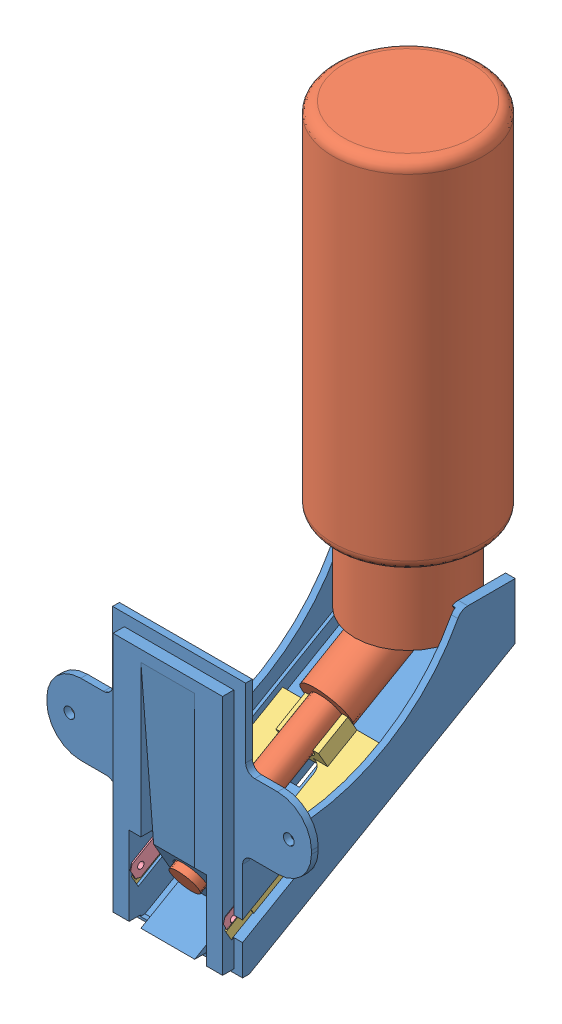
SolidWorks assembly bottleMountAssembly3, configuration Default. Lengths in mm.
Overall size (74.3 196.43 192.12).
5 component instances, 4 part files, 12 mates.
Components (placement in the parent):
- bottleMount_static_v2-1: bottleMount_static_v2 [Default] at (-12.9137 -6.1587 48.6671) size (74.3 72.12 79.72)
- bottle-1: bottle [Default] at (-12.9137 -32.5063 49.017) x (-1 0 0) z (0 0.5 -0.866025) size (42 123.42 150.58)
- bottlePivot-1: bottlePivot [Static] at (-12.9137 -20.4581 13.8552) x (-1 0 0) z (0 0.5 -0.866025) size (31.26 22.01 50.67)
- irOutline_sparkfun-1: irOutline_sparkfun [Default] at (-23.7712 -33.3419 50.4643) x (0 -0.866025 -0.5) z (-1 0 0) size (5 12 4.3)
- irOutline_sparkfun-2: irOutline_sparkfun [Default] at (2.2438 -33.3419 50.4643) x (0 -0.866025 -0.5) z (-1 0 0) size (5 12 4.3)
Mates (geometry in assembly coordinates):
- Concentric1: concentric aligned: cylinder of bottleMount_static_v2-1 through (-12.9137 -22.1373 31.0574) axis (0 -0.5 0.866025) radius 4.3969; cylinder of bottle-1 through (-12.9137 -9.5063 9.1798) axis (0 -0.5 0.866025) radius 4
- Coincident7: coincident anti-aligned: plane of bottleMount_static_v2-1 through (-12.9137 -6.1587 48.6671) normal (1 0 0); plane of bottlePivot-1 through (-12.9137 -20.4581 13.8552) normal (-1 0 0)
- Coincident8: coincident anti-aligned: plane of bottleMount_static_v2-1 through (-28.0267 -31.9572 33.7723) normal (0 0.866025 0.5); plane of bottlePivot-1 through (-12.9137 -15.6956 5.6063) normal (0 -0.866025 -0.5)
- LimitDistance1: limit distance = 0 mm anti-aligned: plane of bottlePivot-1 through (-38.3137 -41.0313 49.489) normal (0 -0.5 0.866025); plane of bottleMount_static_v2-1 through (-12.9137 -15.2328 64.3838) normal (0 0.5 -0.866025)
- Coincident10: coincident anti-aligned: plane of bottle-1 through (-12.9137 -9.5063 9.1798) normal (0 -0.5 0.866025); plane of bottlePivot-1 through (-12.9137 -15.6956 5.6063) normal (0 0.5 -0.866025)
- Coincident11: coincident anti-aligned: plane of bottleMount_static_v2-1 through (-12.9137 -6.1587 48.6671) normal (1 0 0); plane of bottle-1 through (-12.9137 -32.5063 49.017) normal (-1 0 0)
- Coincident12: coincident anti-aligned: plane of bottlePivot-1 through (-12.9137 -26.6275 33.8347) normal (0 0.866025 0.5); plane of irOutline_sparkfun-1 through (-28.0712 -35.507 49.2143) normal (0 -0.866025 -0.5)
- Coincident13: coincident anti-aligned: plane of bottlePivot-1 through (-28.0712 -30.6518 31.5113) normal (1 0 0); plane of irOutline_sparkfun-1 through (-28.0712 -33.3419 50.4643) normal (-1 0 0)
- Coincident14: coincident anti-aligned: plane of bottlePivot-1 through (-12.9137 -40.7813 49.056) normal (0 0.5 -0.866025); plane of irOutline_sparkfun-1 through (-28.0712 -34.5919 52.6294) normal (0 -0.5 0.866025)
- Coincident15: coincident anti-aligned: plane of bottlePivot-1 through (2.2438 -30.6518 31.5113) normal (-1 0 0); plane of irOutline_sparkfun-2 through (2.2438 -33.3419 50.4643) normal (1 0 0)
- Coincident16: coincident anti-aligned: plane of bottlePivot-1 through (-12.9137 -26.6275 33.8347) normal (0 0.866025 0.5); plane of irOutline_sparkfun-2 through (-2.0562 -35.507 49.2143) normal (0 -0.866025 -0.5)
- Coincident17: coincident anti-aligned: plane of bottlePivot-1 through (-12.9137 -40.7813 49.056) normal (0 0.5 -0.866025); plane of irOutline_sparkfun-2 through (-2.0562 -34.5919 52.6294) normal (0 -0.5 0.866025)
